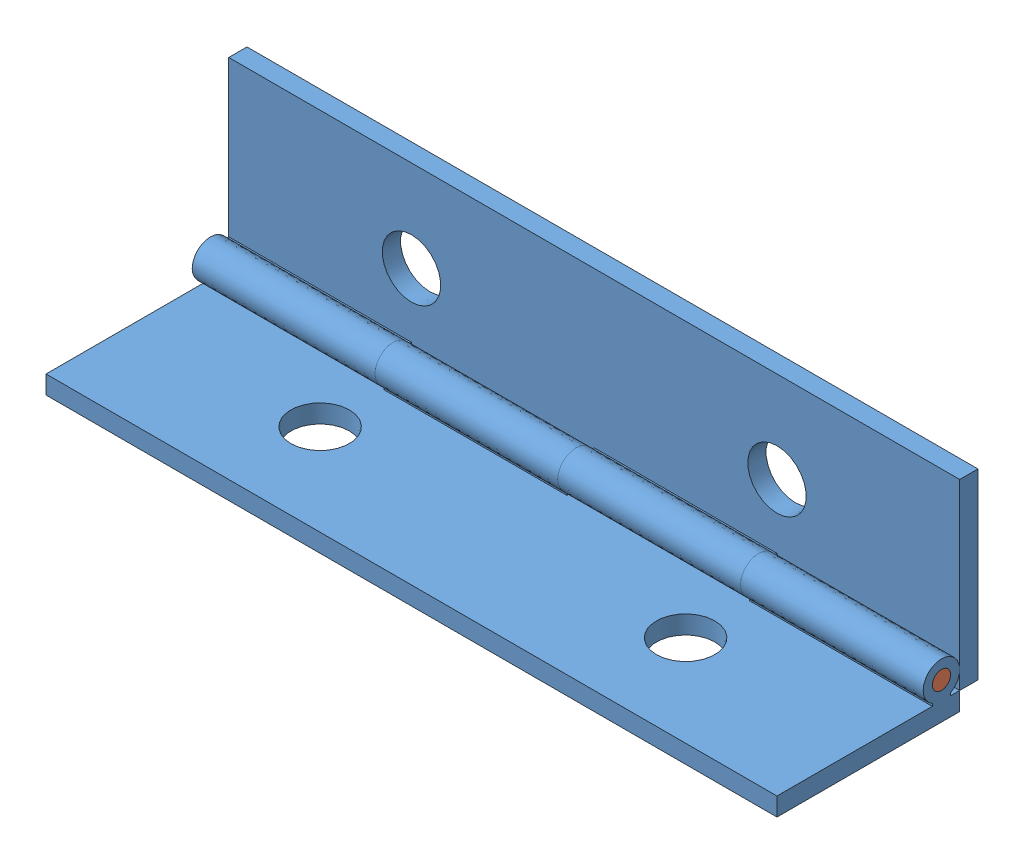
SolidWorks assembly assembledhinge, configuration Default. Lengths in mm.
Overall size (40 11 11).
3 component instances, 2 part files, 5 mates.
Components (placement in the parent):
- Side1-1: Side1 [Default] at (-19.0062 3.8597 7.4071) size (40 3 10)
- hingerod-1: hingerod [Default] at (20.9938 5.8597 -1.5929) x (0 0.229452 0.97332) z (0 -0.97332 0.229452) size (1 40 1)
- Side1-2: Side1 [Default] at (20.9938 14.8597 -3.5929) x (-1 0 0) z (0 1 0) size (40 3 10)
Mates (geometry in assembly coordinates):
- Coincident1: coincident aligned: plane of Side1-1 through (-19.0062 4.8597 7.4071) normal (-1 0 0); plane of Side1-2 through (-19.0062 14.8597 -2.5929) normal (-1 0 0)
- Concentric1: concentric anti-aligned: cylinder of Side1-1 through (-19.0062 5.8597 -1.5929) axis (1 0 0) radius 0.5; cylinder of Side1-2 through (20.9938 5.8597 -1.5929) axis (-1 0 0) radius 0.5
- Concentric2: concentric anti-aligned: cylinder of hingerod-1 through (-19.0062 5.8597 -1.5929) axis (1 0 0) radius 0.5; cylinder of Side1-2 through (20.9938 5.8597 -1.5929) axis (-1 0 0) radius 0.5
- Coincident2: coincident aligned: plane of hingerod-1 through (-19.0062 5.8597 -1.5929) normal (-1 0 0); plane of Side1-2 through (-19.0062 14.8597 -2.5929) normal (-1 0 0)
- Angle1: planar angle = 1.570796 rad aligned: plane of Side1-1 through (-19.0062 4.8597 -2.5929) normal (0 1 0); plane of Side1-2 through (20.9938 4.8597 -2.5929) normal (0 0 1)
